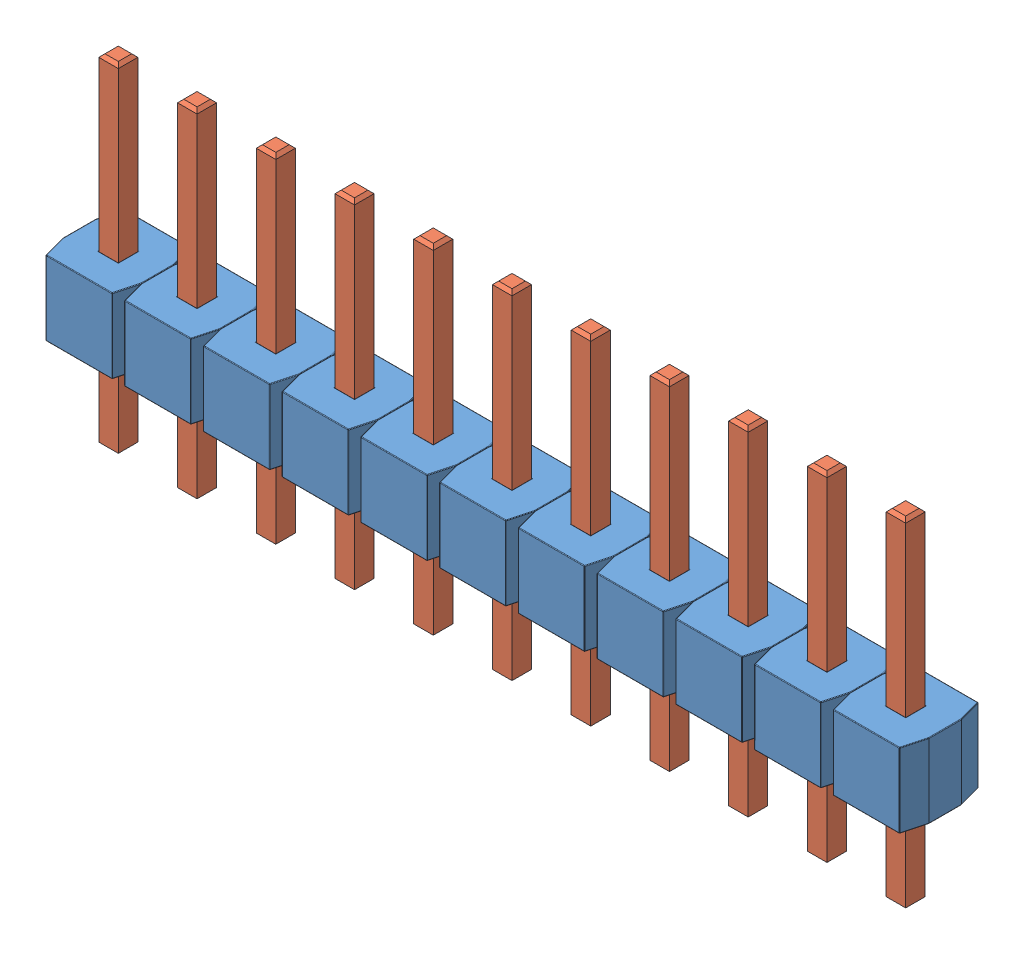
SolidWorks assembly Male Header Pin Config, configuration 11 pin. Lengths in mm.
Overall size (27.94 10.95 2.54).
22 component instances, 2 part files, 1 mates.
Components (placement in the parent):
- Spacer-1: Spacer [Default] at origin
- Male Header Pin-1: Male Header Pin [Default] at (0 -3.03 0) x (0 0 1) z (-1 0 0)
- Spacer-2: Spacer [Default] at (2.54 0 0)
- Male Header Pin-2: Male Header Pin [Default] at (2.54 -3.03 0) x (0 0 1) z (-1 0 0)
- Spacer-3: Spacer [Default] at (5.08 0 0)
- Spacer-4: Spacer [Default] at (7.62 0 0)
- Spacer-5: Spacer [Default] at (10.16 0 0)
- Spacer-6: Spacer [Default] at (12.7 0 0)
- Spacer-7: Spacer [Default] at (15.24 0 0)
- Spacer-8: Spacer [Default] at (17.78 0 0)
- Spacer-9: Spacer [Default] at (20.32 0 0)
- Spacer-10: Spacer [Default] at (22.86 0 0)
- Spacer-11: Spacer [Default] at (25.4 0 0)
- Male Header Pin-3: Male Header Pin [Default] at (5.08 -3.03 0) x (0 0 1) z (-1 0 0)
- Male Header Pin-4: Male Header Pin [Default] at (7.62 -3.03 0) x (0 0 1) z (-1 0 0)
- Male Header Pin-5: Male Header Pin [Default] at (10.16 -3.03 0) x (0 0 1) z (-1 0 0)
- Male Header Pin-6: Male Header Pin [Default] at (12.7 -3.03 0) x (0 0 1) z (-1 0 0)
- Male Header Pin-7: Male Header Pin [Default] at (15.24 -3.03 0) x (0 0 1) z (-1 0 0)
- Male Header Pin-8: Male Header Pin [Default] at (17.78 -3.03 0) x (0 0 1) z (-1 0 0)
- Male Header Pin-9: Male Header Pin [Default] at (20.32 -3.03 0) x (0 0 1) z (-1 0 0)
- Male Header Pin-10: Male Header Pin [Default] at (22.86 -3.03 0) x (0 0 1) z (-1 0 0)
- Male Header Pin-11: Male Header Pin [Default] at (25.4 -3.03 0) x (0 0 1) z (-1 0 0)
Mates (geometry in assembly coordinates):
- ProfileCenter1: profile center = 5.52 mm aligned: plane of Male Header Pin-1 through (0 7.92 0) normal (0 1 0); plane of Spacer-1 through (0 2.4 0) normal (0 1 0)
